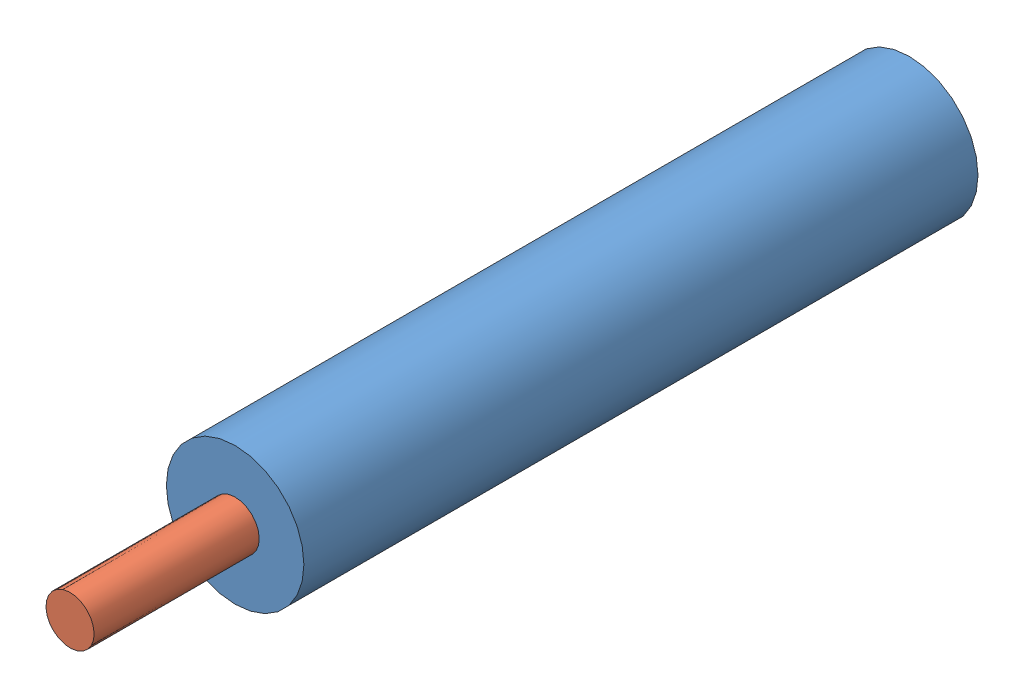
SolidWorks assembly as1, configuration Default. Lengths in mm.
Overall size (20 20 122).
2 component instances, 2 part files, 2 mates.
Components (placement in the parent):
- np5-1: np5 [Default] at (24.0624 45.3576 13.8241) size (20 20 98)
- np6-1: np6 [Default] at (24.0624 45.3576 135.8241) x (-0.976435 0.215811 0) z (0 0 -1) size (15 15 120)
Mates (geometry in assembly coordinates):
- Concentric1: concentric aligned: cylinder of np5-1 through (24.0624 45.3576 106.8241) axis (0 0 1) radius 3.5; cylinder of np6-1 through (24.0624 45.3576 35.8241) axis (0 0 1) radius 3.5
- LimitDistance3: limit distance = 71 mm anti-aligned: plane of np5-1 through (24.0624 45.3576 106.8241) normal (0 0 -1); plane of np6-1 through (24.0624 45.3576 35.8241) normal (0 0 1)
